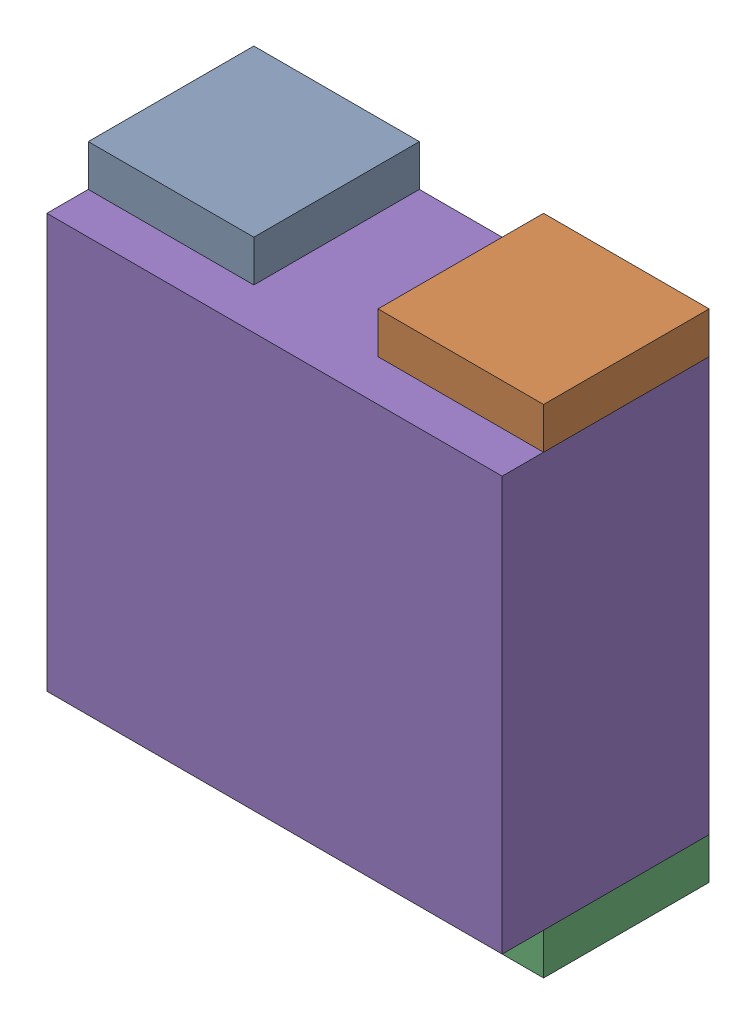
SolidWorks assembly RN21, configuration Default. Lengths in mm.
Overall size (1.1 1.2 0.5).
10 component instances, 2 part files, 0 mates.
Components (placement in the parent):
- 810157616-1: 810157616 [Default] at (128.4 79 0) size (0.4 0.1 0.4)
  - Extruded_12-1: Extruded_12 [Default] at origin size (0.4 0.1 0.4)
- 810157616-2: 810157616 [Default] at (129.1 79 0) size (0.4 0.1 0.4)
  - Extruded_12-1: Extruded_12 [Default] at origin size (0.4 0.1 0.4)
- 810157616-3: 810157616 [Default] at (129.1 77.9 0) size (0.4 0.1 0.4)
  - Extruded_12-1: Extruded_12 [Default] at origin size (0.4 0.1 0.4)
- 810157616-4: 810157616 [Default] at (128.4 77.9 0) size (0.4 0.1 0.4)
  - Extruded_12-1: Extruded_12 [Default] at origin size (0.4 0.1 0.4)
- 810156720-1: 810156720 [Default] at (128.75 78.45 0) size (1.1 1 0.5)
  - Extruded_13-1: Extruded_13 [Default] at origin size (1.1 1 0.5)
